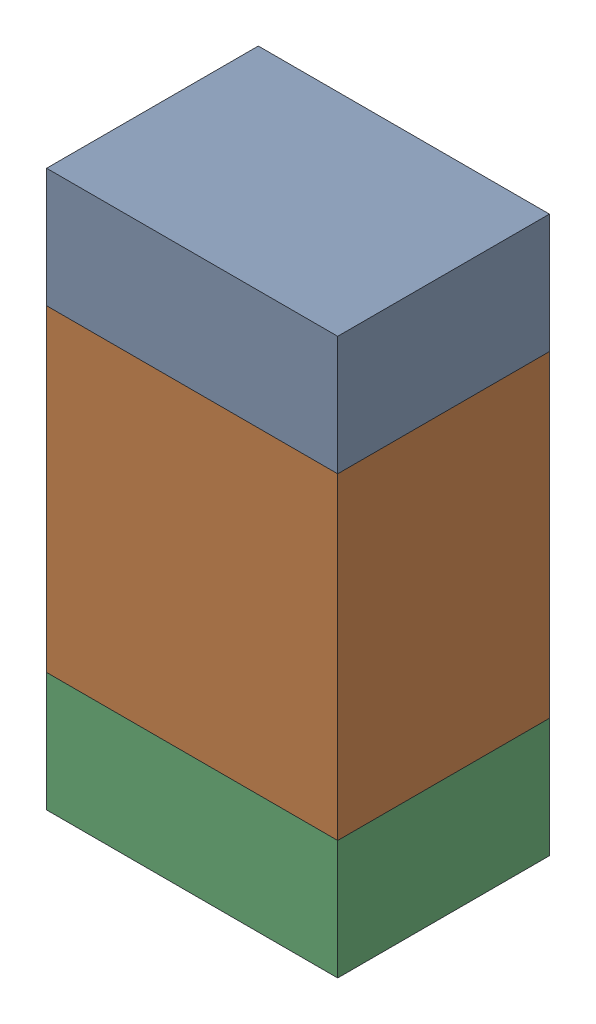
SolidWorks assembly R601_3PCB, configuration Default. Lengths in mm.
Overall size (0.55 1.05 0.4).
6 component instances, 2 part files, 0 mates.
Components (placement in the parent):
- 846483288-1: 846483288 [Default] at (104.7999 96.8624 -2.0638) size (0.55 0.22 0.4)
  - Extruded_12-1: Extruded_12 [Default] at origin size (0.55 0.22 0.4)
- 846483424-1: 846483424 [Default] at (104.7999 96.4499 -2.0638) size (0.55 0.6 0.4)
  - Extruded_13-1: Extruded_13 [Default] at origin size (0.55 0.6 0.4)
- 846483288-2: 846483288 [Default] at (104.7999 96.0374 -2.0638) size (0.55 0.22 0.4)
  - Extruded_12-1: Extruded_12 [Default] at origin size (0.55 0.22 0.4)
